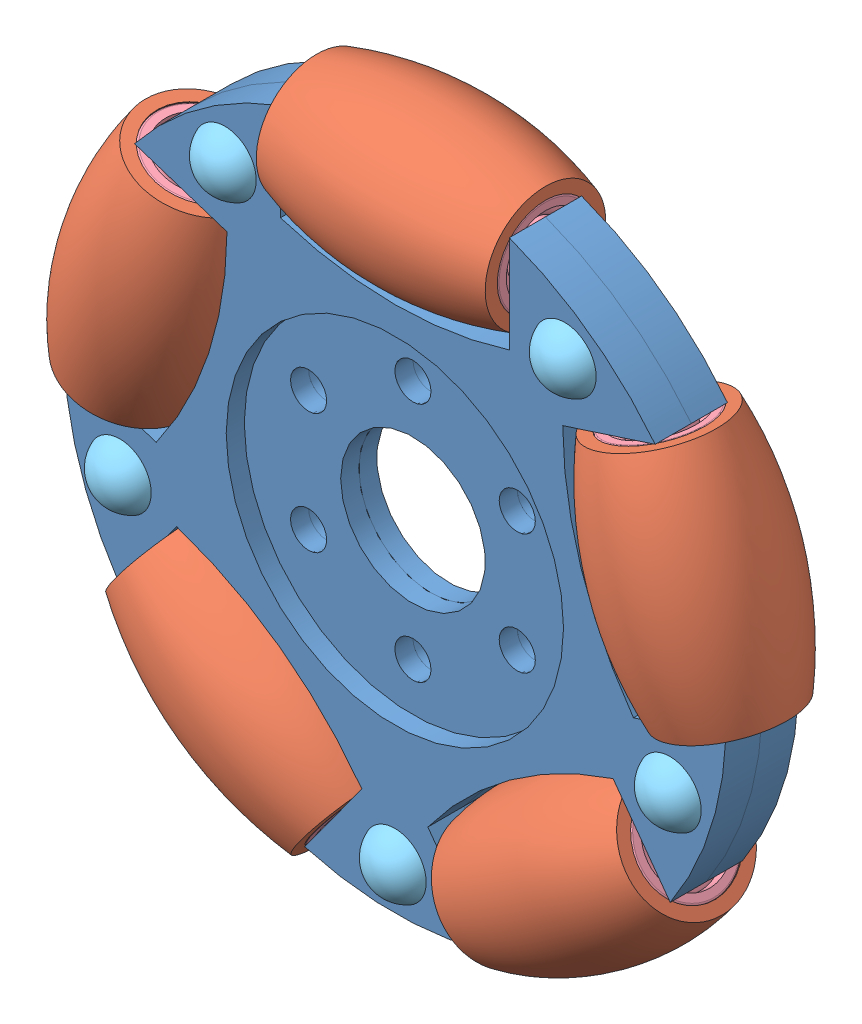
SolidWorks assembly Plate Assembly, configuration Default. Lengths in mm.
Overall size (65.58 62.37 15.81).
32 component instances, 5 part files, 7 mates.
Components (placement in the parent):
- Plate-1: Plate [Default] at (19.0254 28.4997 42.1698) size (54.96 53.31 3)
- Plate-3: Plate [Default] at (19.0254 28.4997 48.1698) x (-1 0 0) z (0 0 -1) size (54.96 53.31 3)
- Roller assenbly-1: Roller assenbly [Default] at (9.5254 51.4997 45.1698) x (1 0 0) z (0 -0.968969 -0.247184) size (22 13 13)
  - Roller-1: Roller [Default] at origin size (19 13 13)
  - Pin-1: Pin [Default] at (9.5 0 0) x (0 -0.246767 -0.969075) z (1 0 0) size (3 3 22)
  - instrument ball bearing_68_am-1: instrument ball bearing_68_am [AFBMA 12.1.4.1 - 0030-8 - 8,SI,NC,8_68] at (17.5 0 0) size (3 8 8)
  - instrument ball bearing_68_am-2: instrument ball bearing_68_am [AFBMA 12.1.4.1 - 0030-8 - 8,SI,NC,8_68] at (1.5 0 0) x (-1 0 0) z (0 -0.924225 -0.381849) size (3 8 8)
- Roller assenbly-2: Roller assenbly [Default] at (-5.7846 26.5721 45.1698) x (0.309017 0.951057 0) z (0.921544 -0.299428 -0.247184) size (22 13 13)
  - Roller-1: Roller [Default] at origin size (19 13 13)
  - Pin-1: Pin [Default] at (9.5 0 0) x (0 -0.246767 -0.969075) z (1 0 0) size (3 3 22)
  - instrument ball bearing_68_am-1: instrument ball bearing_68_am [AFBMA 12.1.4.1 - 0030-8 - 8,SI,NC,8_68] at (17.5 0 0) size (3 8 8)
  - instrument ball bearing_68_am-2: instrument ball bearing_68_am [AFBMA 12.1.4.1 - 0030-8 - 8,SI,NC,8_68] at (1.5 0 0) x (-1 0 0) z (0 -0.924225 -0.381849) size (3 8 8)
- Roller assenbly-3: Roller assenbly [Default] at (13.192 4.3084 45.1698) x (-0.809017 0.587785 0) z (0.569545 0.783912 -0.247184) size (22 13 13)
  - Roller-1: Roller [Default] at origin size (19 13 13)
  - Pin-1: Pin [Default] at (9.5 0 0) x (0 -0.246767 -0.969075) z (1 0 0) size (3 3 22)
  - instrument ball bearing_68_am-1: instrument ball bearing_68_am [AFBMA 12.1.4.1 - 0030-8 - 8,SI,NC,8_68] at (17.5 0 0) size (3 8 8)
  - instrument ball bearing_68_am-2: instrument ball bearing_68_am [AFBMA 12.1.4.1 - 0030-8 - 8,SI,NC,8_68] at (1.5 0 0) x (-1 0 0) z (0 -0.924225 -0.381849) size (3 8 8)
- Roller assenbly-4: Roller assenbly [Default] at (40.2301 15.4763 45.1698) x (-0.809017 -0.587785 0) z (-0.569545 0.783912 -0.247184) size (22 13 13)
  - Roller-1: Roller [Default] at origin size (19 13 13)
  - Pin-1: Pin [Default] at (9.5 0 0) x (0 -0.246767 -0.969075) z (1 0 0) size (3 3 22)
  - instrument ball bearing_68_am-1: instrument ball bearing_68_am [AFBMA 12.1.4.1 - 0030-8 - 8,SI,NC,8_68] at (17.5 0 0) size (3 8 8)
  - instrument ball bearing_68_am-2: instrument ball bearing_68_am [AFBMA 12.1.4.1 - 0030-8 - 8,SI,NC,8_68] at (1.5 0 0) x (-1 0 0) z (0 -0.924225 -0.381849) size (3 8 8)
- Roller assenbly-5: Roller assenbly [Default] at (37.964 44.6422 45.1698) x (0.309017 -0.951057 0) z (-0.921544 -0.299428 -0.247184) size (22 13 13)
  - Roller-1: Roller [Default] at origin size (19 13 13)
  - Pin-1: Pin [Default] at (9.5 0 0) x (0 -0.246767 -0.969075) z (1 0 0) size (3 3 22)
  - instrument ball bearing_68_am-1: instrument ball bearing_68_am [AFBMA 12.1.4.1 - 0030-8 - 8,SI,NC,8_68] at (17.5 0 0) size (3 8 8)
  - instrument ball bearing_68_am-2: instrument ball bearing_68_am [AFBMA 12.1.4.1 - 0030-8 - 8,SI,NC,8_68] at (1.5 0 0) x (-1 0 0) z (0 -0.924225 -0.381849) size (3 8 8)
- rivet 02_din-7: rivet 02_din [DIN 660-3x10-St-A-5.5] at (33.1322 47.9161 42.6698) x (0 0 -1) z (1 0 0) size (9.1 5.2 5.2)
- rivet 02_din-8: rivet 02_din [DIN 660-3x10-St-A-5.5] at (4.9185 47.9161 42.6698) x (0 0 -1) z (0.309017 0.951057 0) size (9.1 5.2 5.2)
- rivet 02_din-9: rivet 02_din [DIN 660-3x10-St-A-5.5] at (-3.8 21.0833 42.6698) x (0 0 -1) z (-0.809017 0.587785 0) size (9.1 5.2 5.2)
- rivet 02_din-10: rivet 02_din [DIN 660-3x10-St-A-5.5] at (19.0254 4.4997 42.6698) x (0 0 -1) z (-0.809017 -0.587785 0) size (9.1 5.2 5.2)
- rivet 02_din-11: rivet 02_din [DIN 660-3x10-St-A-5.5] at (41.8507 21.0833 42.6698) x (0 0 -1) z (0.309017 -0.951057 0) size (9.1 5.2 5.2)
Mates (geometry in assembly coordinates):
- Concentric4: concentric anti-aligned: cylinder of Plate-1 through (19.0254 28.4997 45.1698) axis (0 0 -1) radius 27.5; cylinder of Plate-3 through (19.0254 28.4997 45.1698) axis (0 0 1) radius 27.5
- Concentric5: concentric anti-aligned: cylinder of Plate-1 through (27.6856 33.4997 42.1698) axis (0 0 1) radius 1.5; cylinder of Plate-3 through (27.6856 33.4997 48.1698) axis (0 0 -1) radius 1.5
- Concentric6: concentric aligned: cylinder of Plate-1 through (8.0254 51.4997 45.1698) axis (-1 0 0) radius 1.5; cylinder of Roller assenbly-1/Pin-1 through (30.0254 51.4997 45.1698) axis (-1 0 0) radius 1.5
- Coincident2: coincident anti-aligned: plane of Plate-1 through (30.0254 52.9997 45.1698) normal (-1 0 0); plane of Roller assenbly-1/Pin-1 through (30.0254 51.4997 45.1698) normal (1 0 0)
- Coincident6: coincident anti-aligned: plane of Plate-1 through (64.0389 43.1255 45.1698) normal (0 0 1); plane of Plate-3 through (-25.9881 43.1255 45.1698) normal (0 0 -1)
- Concentric7: concentric anti-aligned: cylinder of Plate-3 through (33.1322 47.9161 48.1698) axis (0 0 -1) radius 1.5; cylinder of rivet 02_din om-7 through (33.1322 47.9161 81.6698) axis (0 0 1) radius 1.5
- Coincident7: coincident anti-aligned: plane of Plate-3 through (-25.9881 43.1255 48.1698) normal (0 0 1); plane of rivet 02_din om-7 through (33.1322 49.4161 48.1698) normal (0 0 -1)
